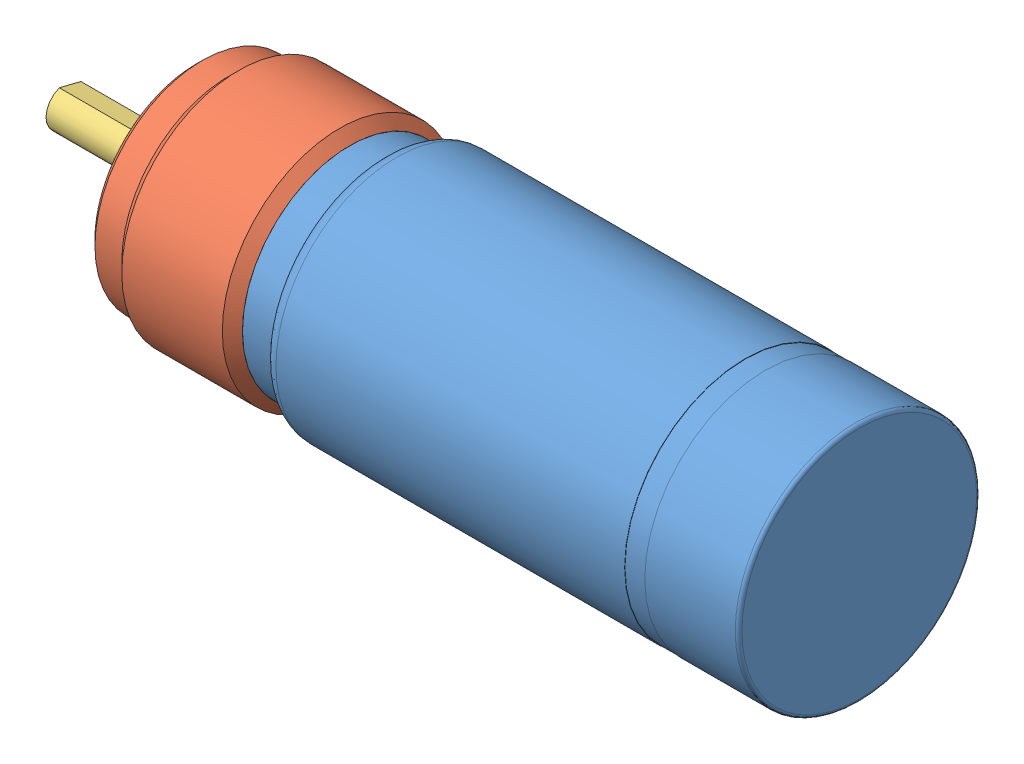
SolidWorks assembly IG320014, configuration По умолчанию. Lengths in mm.
3 component instances, 3 part files, 6 mates.
Components (placement in the parent):
- IG320014 ч2 (мотор)-1: IG320014 ч2 (мотор) [По умолчанию] at origin size (76 36 36)
- IG320014 ч1 (редуктор)-1: IG320014 ч1 (редуктор) [По умолчанию] at origin size (26 35 35)
- IG320014 ч3 (вал)-1: IG320014 ч3 (вал) [По умолчанию] at (16.3 0 0) x (0 0.239677 0.970853) z (0 -0.970853 0.239677) size (6 16.3 6)
Mates (geometry in assembly coordinates):
- Концентричный1: concentric aligned: cylinder of IG320014 ч2 (мотор)-1 through (0 0 0) axis (-1 0 0) radius 18; cylinder of IG320014 ч1 (редуктор)-1 through (0 0 0) axis (-1 0 0) radius 17.5
- Совпадение1: coincident anti-aligned: plane of IG320014 ч2 (мотор)-1 through (42.3 0 0) normal (-1 0 0); plane of IG320014 ч1 (редуктор)-1 through (42.3 0 0) normal (1 0 0)
- Совпадение2: coincident aligned: plane of IG320014 ч1 (редуктор)-1 through (0 0 0) normal (0 1 0); plane of assembly through (0 0 0) normal (0 1 0)
- Совпадение3: coincident aligned: plane of IG320014 ч1 (редуктор)-1 through (0 0 0) normal (0 0 1); plane of assembly through (0 0 0) normal (0 0 1)
- Совпадение4: coincident anti-aligned: plane of IG320014 ч1 (редуктор)-1 through (16.3 0 0) normal (-1 0 0); plane of IG320014 ч3 (вал)-1 through (16.3 0 0) normal (1 0 0)
- Концентричный2: concentric anti-aligned: cylinder of IG320014 ч1 (редуктор)-1 through (0 0 0) axis (-1 0 0) radius 17.5; cylinder of IG320014 ч3 (вал)-1 through (0 0 0) axis (1 0 0) radius 3
